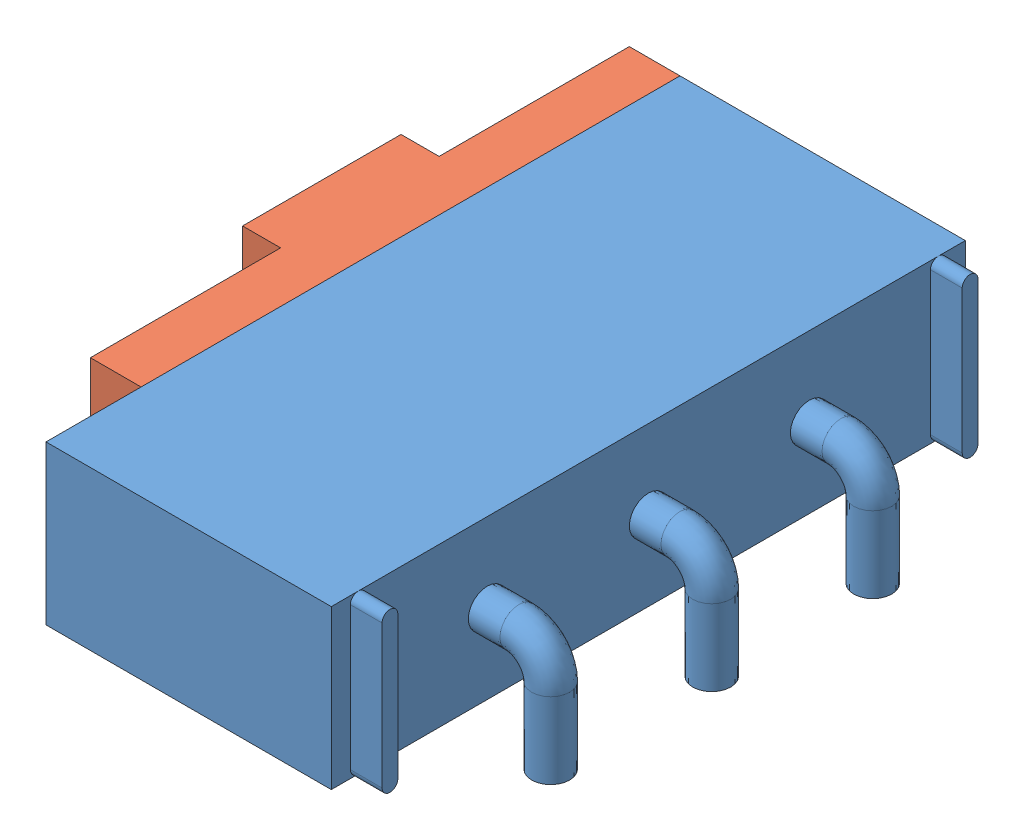
SolidWorks assembly Switch - Assembly, configuration Default. Lengths in mm.
Overall size (7.2 2.95 10).
2 component instances, 2 part files, 3 mates.
Components (placement in the parent):
- Switch - Body-1: Switch - Body [Default] at (1.6382 -0.6065 -0.5877) size (5.8 2.95 10)
- Switch - Rocker-1: Switch - Rocker [Default] at (1.6382 -0.6065 -2.0877) x (0 1 0) z (0 0 1) size (2.5 1.4 8.5)
Mates (geometry in assembly coordinates):
- Coincident2: coincident anti-aligned: plane of Switch - Body-1 through (1.6382 1.8935 -0.5877) normal (-1 0 0); plane of Switch - Rocker-1 through (1.6382 -0.6065 -2.0877) normal (1 0 0)
- Coincident3: coincident aligned: plane of Switch - Body-1 through (1.6382 -0.6065 -0.5877) normal (0 -1 0); plane of Switch - Rocker-1 through (0.8382 -0.6065 -2.0877) normal (0 -1 0)
- LimitDistance1: limit distance = 1.5 mm aligned: plane of Switch - Rocker-1 through (0.8382 -0.6065 -2.0877) normal (0 0 1); plane of Switch - Body-1 through (1.6382 1.8935 -0.5877) normal (0 0 1)
